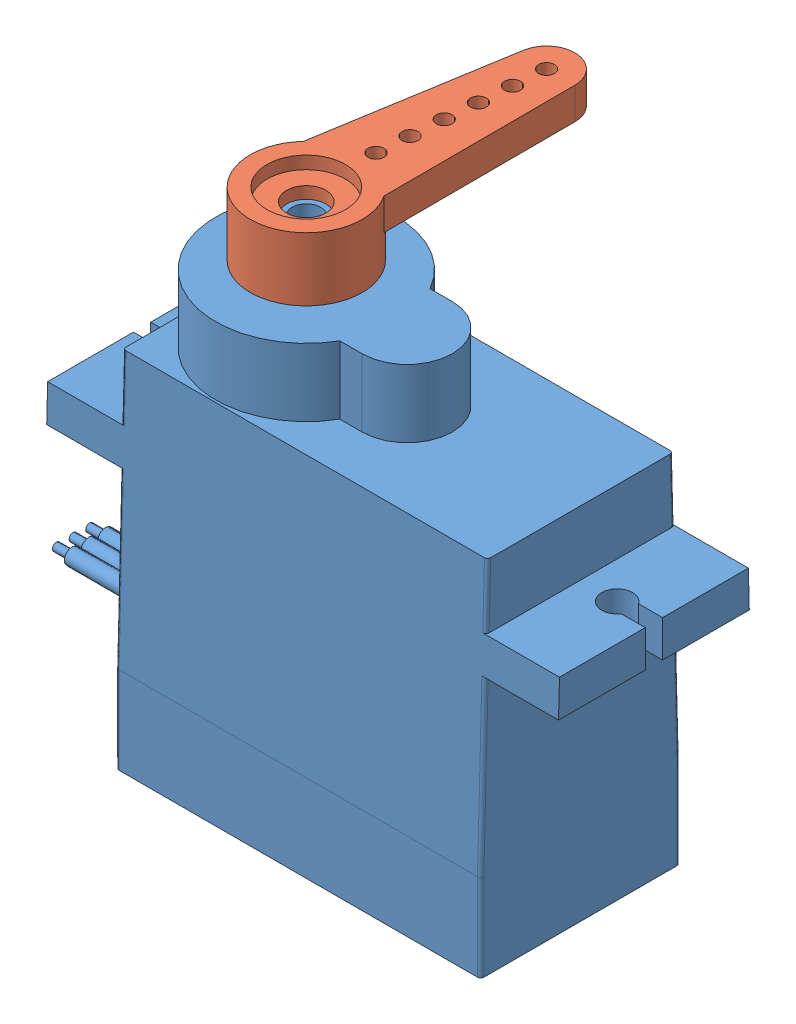
SolidWorks assembly Tower Pro 9g Micro Servo SG90, configuration Default. Lengths in mm.
Overall size (36.67 31.5 22.39).
3 component instances, 3 part files, 4 mates.
Components (placement in the parent):
- Tower Pro 9g Micro Servo SG90-1: Tower Pro 9g Micro Servo SG90 [Default] at origin size (36.67 29.95 12.59)
- SG90 plastic Horn-1: SG90 plastic Horn [Default] at (-1.405 13.16 0) x (0.080382 0 -0.996764) z (0.996764 0 0.080382) size (19.4 4 7.07)
- SM-S2309S-Screw-1: SM-S2309S-Screw [Default] at (-1.405 14.36 0) x (0.707107 0 -0.707107) z (0.707107 0 0.707107) (suppressed, hidden)
Mates (geometry in assembly coordinates):
- Coincident4: coincident anti-aligned: plane of SG90 plastic Horn-1 through (-1.2061 14.36 -2.467) normal (0 1 0); plane of SM-S2309S-Screw-1 through (-0.5741 14.36 -0.8309) normal (0 -1 0)
- Concentric1: concentric aligned: cylinder of SG90 plastic Horn-1 through (-1.405 68.16 0) axis (0 1 0) radius 2.375; cylinder of SM-S2309S-Screw-1 through (-1.405 9.16 0) axis (0 1 0) radius 1.175
- Coincident5: coincident anti-aligned: circle of Tower Pro 9g Micro Servo SG90-1; plane of SG90 plastic Horn-1 through (-1.3049 13.61 -1.241) normal (0 -1 0)
- Concentric2: concentric aligned: cylinder of Tower Pro 9g Micro Servo SG90-1 through (-1.405 9.66 0) axis (0 1 0) radius 2.3; cylinder of SG90 plastic Horn-1 through (-1.405 68.16 0) axis (0 1 0) radius 3.535
